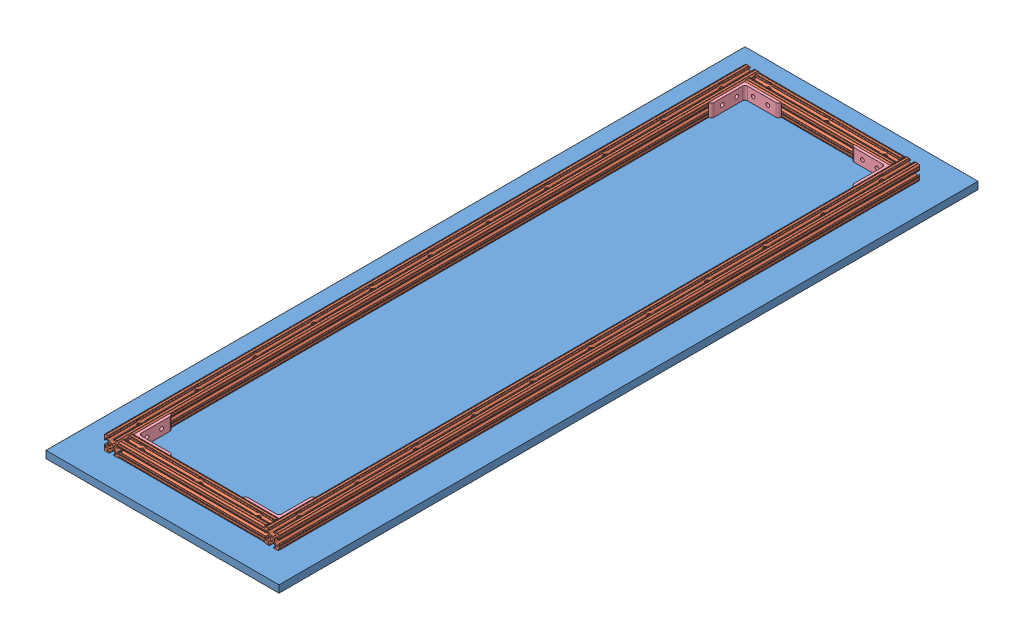
SolidWorks assembly PXL Packing Box, configuration Default. Lengths in mm.
Overall size (406.4 38.1 1219.2).
37 component instances, 4 part files, 18 mates.
Components (placement in the parent):
- PXL Packing Box Base-1: PXL Packing Box Base [Default] at origin size (406.4 12.7 1219.2)
- PXL Packing 8020-1010-1: PXL Packing 8020-1010 [Default] at (139.7 12.7 228.6) size (25.4 25.4 1117.6)
- PXL Packing Wood Screw-2: PXL Packing Wood Screw [1" SCREW] at (139.7 15.8811 177.8) x (1 0 0) z (0 1 0) size (7.72 7.72 27.4)
- PXL Packing 8020-1010-2: PXL Packing 8020-1010 [Short] at (152.4 12.7 215.9) x (0 0 -1) z (1 0 0) size (25.4 25.4 254)
- PXL Packing Wood Screw-1: PXL Packing Wood Screw [1" SCREW] at (101.6 15.8811 215.9) x (1 0 0) z (0 1 0) size (7.72 7.72 27.4)
- PXL Packing Wood Screw-3: PXL Packing Wood Screw [1" SCREW] at (0 15.8811 215.9) x (1 0 0) z (0 1 0) size (7.72 7.72 27.4)
- PXL Packing Wood Screw-4: PXL Packing Wood Screw [1" SCREW] at (-101.6 15.8811 215.9) x (1 0 0) z (0 1 0) size (7.72 7.72 27.4)
- PXL Packing Wood Screw-5: PXL Packing Wood Screw [1" SCREW] at (139.7 15.8811 76.2) x (1 0 0) z (0 1 0) size (7.72 7.72 27.4)
- PXL Packing Wood Screw-6: PXL Packing Wood Screw [1" SCREW] at (139.7 15.8811 -25.4) x (1 0 0) z (0 1 0) size (7.72 7.72 27.4)
- PXL Packing Wood Screw-7: PXL Packing Wood Screw [1" SCREW] at (139.7 15.8811 -127) x (1 0 0) z (0 1 0) size (7.72 7.72 27.4)
- PXL Packing Wood Screw-8: PXL Packing Wood Screw [1" SCREW] at (139.7 15.8811 -228.6) x (1 0 0) z (0 1 0) size (7.72 7.72 27.4)
- PXL Packing Wood Screw-9: PXL Packing Wood Screw [1" SCREW] at (139.7 15.8811 -330.2) x (1 0 0) z (0 1 0) size (7.72 7.72 27.4)
- PXL Packing Wood Screw-10: PXL Packing Wood Screw [1" SCREW] at (139.7 15.8811 -431.8) x (1 0 0) z (0 1 0) size (7.72 7.72 27.4)
- PXL Packing Wood Screw-11: PXL Packing Wood Screw [1" SCREW] at (139.7 15.8811 -533.4) x (1 0 0) z (0 1 0) size (7.72 7.72 27.4)
- PXL Packing Wood Screw-12: PXL Packing Wood Screw [1" SCREW] at (139.7 15.8811 -635) x (1 0 0) z (0 1 0) size (7.72 7.72 27.4)
- PXL Packing Wood Screw-13: PXL Packing Wood Screw [1" SCREW] at (139.7 15.8811 -736.6) x (1 0 0) z (0 1 0) size (7.72 7.72 27.4)
- PXL Packing Wood Screw-14: PXL Packing Wood Screw [1" SCREW] at (139.7 15.8811 -838.2) x (1 0 0) z (0 1 0) size (7.72 7.72 27.4)
- PXL Packing 8020-1010-3: PXL Packing 8020-1010 [Default] at (-139.7 12.7 -889.0005) x (-1 0 0) z (0 0 -1) size (25.4 25.4 1117.6)
- PXL Packing Wood Screw-15: PXL Packing Wood Screw [1" SCREW] at (-139.7 15.8811 76.1875) x (-1 0 0) z (0 1 0) size (7.72 7.72 27.4)
- PXL Packing Wood Screw-16: PXL Packing Wood Screw [1" SCREW] at (-139.7 15.8811 -25.4125) x (-1 0 0) z (0 1 0) size (7.72 7.72 27.4)
- PXL Packing Wood Screw-17: PXL Packing Wood Screw [1" SCREW] at (-139.7 15.8811 -127.0125) x (-1 0 0) z (0 1 0) size (7.72 7.72 27.4)
- PXL Packing Wood Screw-18: PXL Packing Wood Screw [1" SCREW] at (-139.7 15.8811 -228.6125) x (-1 0 0) z (0 1 0) size (7.72 7.72 27.4)
- PXL Packing Wood Screw-19: PXL Packing Wood Screw [1" SCREW] at (-139.7 15.8811 -330.2125) x (-1 0 0) z (0 1 0) size (7.72 7.72 27.4)
- PXL Packing Wood Screw-20: PXL Packing Wood Screw [1" SCREW] at (-139.7 15.8811 -431.8125) x (-1 0 0) z (0 1 0) size (7.72 7.72 27.4)
- PXL Packing Wood Screw-21: PXL Packing Wood Screw [1" SCREW] at (-139.7 15.8811 -533.4125) x (-1 0 0) z (0 1 0) size (7.72 7.72 27.4)
- PXL Packing Wood Screw-22: PXL Packing Wood Screw [1" SCREW] at (-139.7 15.8811 -635.0125) x (-1 0 0) z (0 1 0) size (7.72 7.72 27.4)
- PXL Packing Wood Screw-23: PXL Packing Wood Screw [1" SCREW] at (-139.7 15.8811 -736.6125) x (-1 0 0) z (0 1 0) size (7.72 7.72 27.4)
- PXL Packing Wood Screw-24: PXL Packing Wood Screw [1" SCREW] at (-139.7 15.8811 -838.2125) x (-1 0 0) z (0 1 0) size (7.72 7.72 27.4)
- PXL Packing 8020-1010-4: PXL Packing 8020-1010 [Short] at (-152.4 12.7 -876.3) x (0 0 1) z (-1 0 0) size (25.4 25.4 254)
- PXL Packing Wood Screw-25: PXL Packing Wood Screw [1" SCREW] at (0 15.8811 -876.2875) x (1 0 0) z (0 1 0) size (7.72 7.72 27.4)
- PXL Packing Wood Screw-26: PXL Packing Wood Screw [1" SCREW] at (-101.6 15.8811 -876.2875) x (1 0 0) z (0 1 0) size (7.72 7.72 27.4)
- PXL Packing Wood Screw-27: PXL Packing Wood Screw [1" SCREW] at (101.6 15.8811 -876.2875) x (1 0 0) z (0 1 0) size (7.72 7.72 27.4)
- PXL Packing Wood Screw-28: PXL Packing Wood Screw [1" SCREW] at (-139.7 15.8811 177.7875) x (-1 0 0) z (0 1 0) size (7.72 7.72 27.4)
- PXL Packing 8020-4101-1: PXL Packing 8020-4101 [Default] at (103.0292 1.5875 173.5939) x (0 1 0) z (-1 0 0) size (22.23 63.5 63.5)
- PXL Packing 8020-4101-2: PXL Packing 8020-4101 [Default] at (-103.0292 23.8125 173.5939) x (0 -1 0) z (1 0 0) size (22.23 63.5 63.5)
- PXL Packing 8020-4101-3: PXL Packing 8020-4101 [Default] at (103.0292 23.8125 -833.9939) x (0 -1 0) z (-1 0 0) size (22.23 63.5 63.5)
- PXL Packing 8020-4101-4: PXL Packing 8020-4101 [Default] at (-103.0292 1.5875 -833.9939) x (0 1 0) z (1 0 0) size (22.23 63.5 63.5)
Mates (geometry in assembly coordinates):
- Coincident49: coincident anti-aligned: plane of PXL Packing Box Base-1 through (0 0 0) normal (0 1 0); plane of PXL Packing 8020-1010-1 through (146.0331 0 -889) normal (0 -1 0)
- Width1: width anti-aligned: plane of PXL Packing 8020-1010-1 through (137.9907 5.0292 228.6) normal (0 0 1); plane of PXL Packing 8020-1010-1 through (137.9907 5.0292 -889) normal (0 0 -1); plane of PXL Packing Box Base-1 through (-203.2 -12.7 -939.8) normal (0 0 -1); plane of PXL Packing Box Base-1 through (-203.2 -12.7 279.4) normal (0 0 1)
- Concentric34: concentric anti-aligned: cylinder of PXL Packing 8020-1010-1 through (139.7 25.4 177.8) axis (0 1 0) radius 3.2639; circle of PXL Packing Wood Screw-2
- Coincident55: coincident: circle of PXL Packing 8020-1010-1; cone of PXL Packing Wood Screw-2 through (139.7 17.8811 177.8) axis (0 -1 0)
- Coincident56: coincident aligned: plane of PXL Packing 8020-1010-1 through (139.7 12.7 228.6) normal (0 1 0); plane of PXL Packing 8020-1010-2
- Distance5: distance = 12.7 mm anti-aligned: plane of PXL Packing 8020-1010-2 through (152.4 12.7 215.9) normal (0 0 -1); plane of PXL Packing 8020-1010-1 through (139.7 12.7 228.6) normal (0 0 1)
- Concentric35: concentric anti-aligned: cylinder of PXL Packing 8020-1010-2 through (101.6 25.4 215.9) axis (0 1 0) radius 3.2639; circle of PXL Packing Wood Screw-1
- Coincident59: coincident anti-aligned: circle of PXL Packing 8020-1010-2; cone of PXL Packing Wood Screw-1 through (101.6 17.8811 215.9) axis (0 -1 0)
- Coincident60: coincident aligned: plane of PXL Packing Box Base-1 through (0 0 0) normal (1 0 0); plane of assembly through (0 0 0) normal (1 0 0)
- Coincident61: coincident aligned: plane of PXL Packing Box Base-1 through (0 0 0) normal (0 1 0); plane of assembly through (0 0 0) normal (0 1 0)
- Coincident62: coincident aligned: plane of PXL Packing Box Base-1 through (0 0 0) normal (0 0 1); plane of assembly through (0 0 0) normal (0 0 1)
- Symmetric1: symmetric aligned: plane of PXL Packing 8020-1010-2 through (127 0 190.5) normal (1 0 0); plane of PXL Packing 8020-1010-2 through (-127 0 241.3) normal (-1 0 0); plane of assembly through (0 0 0) normal (1 0 0)
- Coincident63: coincident anti-aligned: plane of PXL Packing 8020-1010-1 through (127 19.0331 -889) normal (-1 0 0); plane of PXL Packing 8020-1010-2 through (127 0 190.5) normal (1 0 0)
- Parallel1: parallel aligned: plane of PXL Packing Wood Screw-1; plane of assembly through (0 0 0) normal (1 0 0)
- Parallel2: parallel aligned: plane of PXL Packing Wood Screw-2; plane of assembly through (0 0 0) normal (1 0 0)
- Coincident64: coincident anti-aligned: plane of PXL Packing 8020-1010-2 through (-965.2 19.0331 203.2) normal (0 0 -1); plane of PXL Packing 8020-4101-1 through (127 23.8125 203.2) normal (0 0 1)
- Coincident65: coincident anti-aligned: plane of PXL Packing 8020-1010-1 through (127 19.0331 -889) normal (-1 0 0); plane of PXL Packing 8020-4101-1 through (127 23.8125 203.2) normal (1 0 0)
- Symmetric2: symmetric aligned: plane of PXL Packing 8020-1010-1 through (139.7 12.7 228.6) normal (0 1 0); plane of PXL Packing 8020-4101-1 through (68.2752 1.5875 203.2) normal (0 -1 0); plane of PXL Packing 8020-4101-1 through (68.2752 23.8125 203.2) normal (0 1 0)
